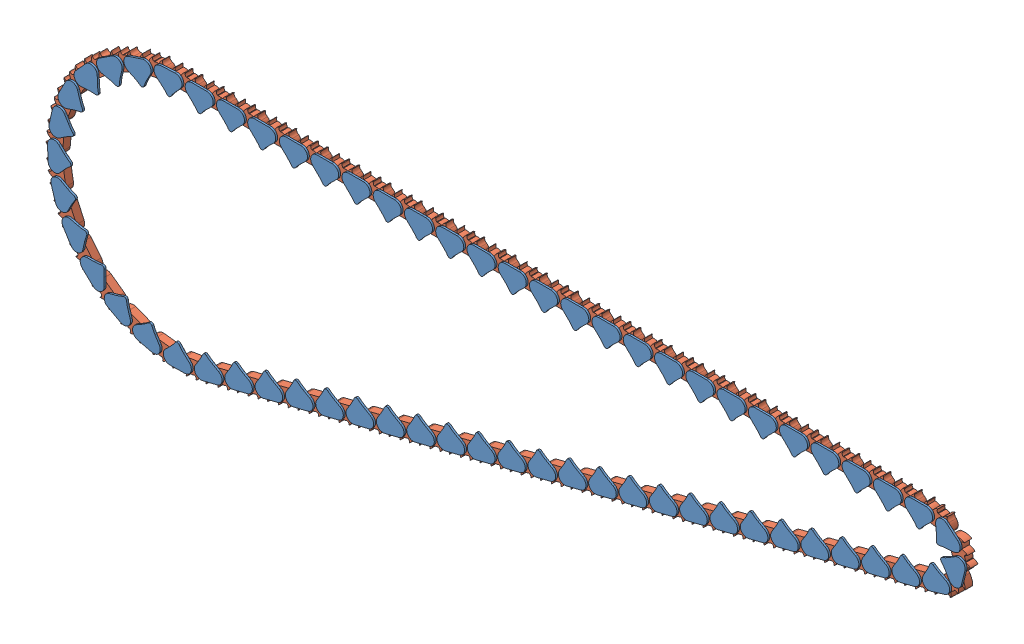
SolidWorks assembly Assem3a, configuration Default. Lengths in mm.
Overall size (244.35 69.57 2.5).
128 component instances, 2 part files, 1 mates.
Components (placement in the parent):
- Inner Part-203: Inner Part [Default] at (-96.4247 54.6348 717.6655) x (-1 0 0) z (0 0 -1) size (7.41 6.1 2.5)
- Teeth-326: Teeth [Default] at (-88.1792 54.6348 717.1655) x (-1 0 0) z (0 0 -1) size (7.83 4.36 2)
- Teeth-327: Teeth [Default] at (-96.4247 54.6348 717.1655) x (-1 0 0) z (0 0 -1) size (7.83 4.36 2)
- Teeth-328: Teeth [Default] at (-104.6702 54.6348 717.1655) x (-1 0 0) z (0 0 -1) size (7.83 4.36 2)
- Teeth-329: Teeth [Default] at (-112.9157 54.6348 717.1655) x (-1 0 0) z (0 0 -1) size (7.83 4.36 2)
- Teeth-330: Teeth [Default] at (-121.1992 54.8708 717.1655) x (-0.981981 -0.188977 0) z (0 0 -1) size (7.83 4.36 2)
- Teeth-331: Teeth [Default] at (-129.3721 53.4391 717.1655) x (-0.901342 -0.433108 0) z (0 0 -1) size (7.83 4.36 2)
- Teeth-332: Teeth [Default] at (-136.91 49.971 717.1655) x (-0.761025 -0.648722 0) z (0 0 -1) size (7.83 4.36 2)
- Teeth-333: Teeth [Default] at (-143.3138 44.6946 717.1655) x (-0.570216 -0.821495 0) z (0 0 -1) size (7.83 4.36 2)
- Teeth-334: Teeth [Default] at (-148.1586 37.9584 717.1655) x (-0.341506 -0.93988 0) z (0 0 -1) size (7.83 4.36 2)
- Teeth-335: Teeth [Default] at (-151.1223 30.2082 717.1655) x (-0.090085 -0.995934 0) z (0 0 -1) size (7.83 4.36 2)
- Teeth-336: Teeth [Default] at (-152.0079 21.9581 717.1655) x (0.167294 -0.985907 0) z (0 0 -1) size (7.83 4.36 2)
- Teeth-337: Teeth [Default] at (-150.7568 13.7555 717.1655) x (0.413488 -0.91051 0) z (0 0 -1) size (7.83 4.36 2)
- Teeth-338: Teeth [Default] at (-147.4526 6.1443 717.1655) x (0.632156 -0.774841 0) z (0 0 -1) size (7.83 4.36 2)
- Teeth-339: Teeth [Default] at (-142.3155 -0.3715 717.1655) x (0.808868 -0.58799 0) z (0 0 -1) size (7.83 4.36 2)
- Teeth-340: Teeth [Default] at (-135.6864 -5.3616 717.1655) x (0.932034 -0.36237 0) z (0 0 -1) size (7.83 4.36 2)
- Teeth-341: Teeth [Default] at (-128.0043 -8.497 717.1655) x (0.993609 -0.112873 0) z (0 0 -1) size (7.83 4.36 2)
- Teeth-342: Teeth [Default] at (-119.7768 -9.5711 717.1655) x (0.989565 0.144089 0) z (0 0 -1) size (7.83 4.36 2)
- Teeth-343: Teeth [Default] at (-111.6404 -8.2623 717.1655) x (0.97022 0.242226 0) z (0 0 -1) size (7.83 4.36 2)
- Teeth-344: Teeth [Default] at (-103.6404 -6.265 717.1655) x (0.97022 0.242226 0) z (0 0 -1) size (7.83 4.36 2)
- Teeth-345: Teeth [Default] at (-95.6405 -4.2677 717.1655) x (0.97022 0.242226 0) z (0 0 -1) size (7.83 4.36 2)
- Teeth-346: Teeth [Default] at (-87.6405 -2.2704 717.1655) x (0.97022 0.242226 0) z (0 0 -1) size (7.83 4.36 2)
- Teeth-347: Teeth [Default] at (-79.6406 -0.2732 717.1655) x (0.97022 0.242226 0) z (0 0 -1) size (7.83 4.36 2)
- Teeth-348: Teeth [Default] at (-71.6406 1.7241 717.1655) x (0.97022 0.242226 0) z (0 0 -1) size (7.83 4.36 2)
- Teeth-349: Teeth [Default] at (-63.6407 3.7214 717.1655) x (0.97022 0.242226 0) z (0 0 -1) size (7.83 4.36 2)
- Teeth-350: Teeth [Default] at (-55.6408 5.7187 717.1655) x (0.97022 0.242226 0) z (0 0 -1) size (7.83 4.36 2)
- Teeth-351: Teeth [Default] at (-47.6408 7.7159 717.1655) x (0.97022 0.242226 0) z (0 0 -1) size (7.83 4.36 2)
- Teeth-352: Teeth [Default] at (-39.6409 9.7132 717.1655) x (0.97022 0.242226 0) z (0 0 -1) size (7.83 4.36 2)
- Teeth-353: Teeth [Default] at (-31.6409 11.7105 717.1655) x (0.97022 0.242226 0) z (0 0 -1) size (7.83 4.36 2)
- Teeth-354: Teeth [Default] at (-23.641 13.7078 717.1655) x (0.97022 0.242226 0) z (0 0 -1) size (7.83 4.36 2)
- Teeth-355: Teeth [Default] at (-15.641 15.705 717.1655) x (0.97022 0.242226 0) z (0 0 -1) size (7.83 4.36 2)
- Teeth-356: Teeth [Default] at (-7.6411 17.7023 717.1655) x (0.97022 0.242226 0) z (0 0 -1) size (7.83 4.36 2)
- Teeth-357: Teeth [Default] at (0.3589 19.6996 717.1655) x (0.97022 0.242226 0) z (0 0 -1) size (7.83 4.36 2)
- Teeth-358: Teeth [Default] at (8.3588 21.6969 717.1655) x (0.97022 0.242226 0) z (0 0 -1) size (7.83 4.36 2)
- Teeth-359: Teeth [Default] at (16.3587 23.6941 717.1655) x (0.97022 0.242226 0) z (0 0 -1) size (7.83 4.36 2)
- Teeth-360: Teeth [Default] at (24.3587 25.6914 717.1655) x (0.97022 0.242226 0) z (0 0 -1) size (7.83 4.36 2)
- Teeth-361: Teeth [Default] at (32.3586 27.6887 717.1655) x (0.97022 0.242226 0) z (0 0 -1) size (7.83 4.36 2)
- Teeth-362: Teeth [Default] at (40.3586 29.686 717.1655) x (0.97022 0.242226 0) z (0 0 -1) size (7.83 4.36 2)
- Teeth-363: Teeth [Default] at (48.3585 31.6832 717.1655) x (0.97022 0.242226 0) z (0 0 -1) size (7.83 4.36 2)
- Teeth-364: Teeth [Default] at (56.3585 33.6805 717.1655) x (0.97022 0.242226 0) z (0 0 -1) size (7.83 4.36 2)
- Teeth-365: Teeth [Default] at (64.3584 35.6778 717.1655) x (0.97022 0.242226 0) z (0 0 -1) size (7.83 4.36 2)
- Teeth-366: Teeth [Default] at (72.3584 37.675 717.1655) x (0.97022 0.242226 0) z (0 0 -1) size (7.83 4.36 2)
- Teeth-367: Teeth [Default] at (80.9343 38.7236 717.1655) x (0.720928 0.69301 0) z (0 0 -1) size (7.83 4.36 2)
- Teeth-368: Teeth [Default] at (87.597 44.8671 717.1655) x (-0.304912 0.95238 0) z (0 0 -1) size (7.83 4.36 2)
- Teeth-369: Teeth [Default] at (85.008 53.5084 717.1655) x (-0.986387 0.164442 0) z (0 0 -1) size (7.83 4.36 2)
- Teeth-370: Teeth [Default] at (76.8558 54.6348 717.1655) x (-1 0 0) z (0 0 -1) size (7.83 4.36 2)
- Teeth-371: Teeth [Default] at (68.6103 54.6348 717.1655) x (-1 0 0) z (0 0 -1) size (7.83 4.36 2)
- Teeth-372: Teeth [Default] at (60.3648 54.6348 717.1655) x (-1 0 0) z (0 0 -1) size (7.83 4.36 2)
- Teeth-373: Teeth [Default] at (52.1193 54.6348 717.1655) x (-1 0 0) z (0 0 -1) size (7.83 4.36 2)
- Teeth-374: Teeth [Default] at (43.8738 54.6348 717.1655) x (-1 0 0) z (0 0 -1) size (7.83 4.36 2)
- Teeth-375: Teeth [Default] at (35.6283 54.6348 717.1655) x (-1 0 0) z (0 0 -1) size (7.83 4.36 2)
- Teeth-376: Teeth [Default] at (27.3828 54.6348 717.1655) x (-1 0 0) z (0 0 -1) size (7.83 4.36 2)
- Teeth-377: Teeth [Default] at (19.1373 54.6348 717.1655) x (-1 0 0) z (0 0 -1) size (7.83 4.36 2)
- Teeth-378: Teeth [Default] at (10.8918 54.6348 717.1655) x (-1 0 0) z (0 0 -1) size (7.83 4.36 2)
- Teeth-379: Teeth [Default] at (2.6463 54.6348 717.1655) x (-1 0 0) z (0 0 -1) size (7.83 4.36 2)
- Teeth-380: Teeth [Default] at (-5.5992 54.6348 717.1655) x (-1 0 0) z (0 0 -1) size (7.83 4.36 2)
- Teeth-381: Teeth [Default] at (-13.8447 54.6348 717.1655) x (-1 0 0) z (0 0 -1) size (7.83 4.36 2)
- Teeth-382: Teeth [Default] at (-22.0902 54.6348 717.1655) x (-1 0 0) z (0 0 -1) size (7.83 4.36 2)
- Teeth-383: Teeth [Default] at (-30.3357 54.6348 717.1655) x (-1 0 0) z (0 0 -1) size (7.83 4.36 2)
- Teeth-384: Teeth [Default] at (-38.5812 54.6348 717.1655) x (-1 0 0) z (0 0 -1) size (7.83 4.36 2)
- Teeth-385: Teeth [Default] at (-46.8267 54.6348 717.1655) x (-1 0 0) z (0 0 -1) size (7.83 4.36 2)
- Teeth-386: Teeth [Default] at (-55.0722 54.6348 717.1655) x (-1 0 0) z (0 0 -1) size (7.83 4.36 2)
- Teeth-387: Teeth [Default] at (-63.3177 54.6348 717.1655) x (-1 0 0) z (0 0 -1) size (7.83 4.36 2)
- Teeth-388: Teeth [Default] at (-71.5632 54.6348 717.1655) x (-1 0 0) z (0 0 -1) size (7.83 4.36 2)
- Teeth-389: Teeth [Default] at (-79.8087 54.6348 717.1655) x (-1 0 0) z (0 0 -1) size (7.83 4.36 2)
- Inner Part-204: Inner Part [Default] at (-104.6702 54.6348 717.6655) x (-1 0 0) z (0 0 -1) size (7.41 6.1 2.5)
- Inner Part-205: Inner Part [Default] at (-112.9157 54.6348 717.6655) x (-1 0 0) z (0 0 -1) size (7.41 6.1 2.5)
- Inner Part-206: Inner Part [Default] at (-121.1586 54.5493 717.6655) x (-0.998125 -0.061215 0) z (0 0 -1) size (7.41 6.1 2.5)
- Inner Part-207: Inner Part [Default] at (-129.2509 53.1385 717.6655) x (-0.949546 -0.313629 0) z (0 0 -1) size (7.41 6.1 2.5)
- Inner Part-208: Inner Part [Default] at (-136.716 49.7111 717.6655) x (-0.838157 -0.545429 0) z (0 0 -1) size (7.41 6.1 2.5)
- Inner Part-209: Inner Part [Default] at (-143.0597 44.4928 717.6655) x (-0.671217 -0.741261 0) z (0 0 -1) size (7.41 6.1 2.5)
- Inner Part-210: Inner Part [Default] at (-147.8612 37.8281 717.6655) x (-0.459699 -0.888075 0) z (0 0 -1) size (7.41 6.1 2.5)
- Inner Part-211: Inner Part [Default] at (-150.8015 30.1582 717.6655) x (-0.217611 -0.976036 0) z (0 0 -1) size (7.41 6.1 2.5)
- Inner Part-212: Inner Part [Default] at (-151.685 21.9916 717.6655) x (0.038936 -0.999242 0) z (0 0 -1) size (7.41 6.1 2.5)
- Inner Part-213: Inner Part [Default] at (-150.4533 13.8703 717.6655) x (0.292843 -0.956161 0) z (0 0 -1) size (7.41 6.1 2.5)
- Inner Part-214: Inner Part [Default] at (-147.1886 6.3327 717.6655) x (0.527221 -0.849728 0) z (0 0 -1) size (7.41 6.1 2.5)
- Inner Part-215: Inner Part [Default] at (-142.1084 -0.1222 717.6655) x (0.726557 -0.687106 0) z (0 0 -1) size (7.41 6.1 2.5)
- Inner Part-216: Inner Part [Default] at (-135.5498 -5.0679 717.6655) x (0.877737 -0.479142 0) z (0 0 -1) size (7.41 6.1 2.5)
- Inner Part-217: Inner Part [Default] at (-127.9471 -8.1782 717.6655) x (0.970871 -0.239604 0) z (0 0 -1) size (7.41 6.1 2.5)
- Inner Part-218: Inner Part [Default] at (-119.8028 -9.2482 717.6655) x (0.999876 0.015731 0) z (0 0 -1) size (7.41 6.1 2.5)
- Inner Part-219: Inner Part [Default] at (-111.6429 -8.2518 717.6655) x (0.971247 0.238075 0) z (0 0 -1) size (7.41 6.1 2.5)
- Inner Part-220: Inner Part [Default] at (-103.6404 -6.265 717.6655) x (0.97022 0.242226 0) z (0 0 -1) size (7.41 6.1 2.5)
- Inner Part-221: Inner Part [Default] at (-95.6405 -4.2677 717.6655) x (0.97022 0.242226 0) z (0 0 -1) size (7.41 6.1 2.5)
- Inner Part-222: Inner Part [Default] at (-87.6405 -2.2704 717.6655) x (0.97022 0.242226 0) z (0 0 -1) size (7.41 6.1 2.5)
- Inner Part-223: Inner Part [Default] at (-79.6406 -0.2732 717.6655) x (0.97022 0.242226 0) z (0 0 -1) size (7.41 6.1 2.5)
- Inner Part-224: Inner Part [Default] at (-71.6406 1.7241 717.6655) x (0.97022 0.242226 0) z (0 0 -1) size (7.41 6.1 2.5)
- Inner Part-225: Inner Part [Default] at (-63.6407 3.7214 717.6655) x (0.97022 0.242226 0) z (0 0 -1) size (7.41 6.1 2.5)
- Inner Part-226: Inner Part [Default] at (-55.6408 5.7187 717.6655) x (0.97022 0.242226 0) z (0 0 -1) size (7.41 6.1 2.5)
- Inner Part-227: Inner Part [Default] at (-47.6408 7.7159 717.6655) x (0.97022 0.242226 0) z (0 0 -1) size (7.41 6.1 2.5)
- Inner Part-228: Inner Part [Default] at (-39.6409 9.7132 717.6655) x (0.97022 0.242226 0) z (0 0 -1) size (7.41 6.1 2.5)
- Inner Part-229: Inner Part [Default] at (-31.6409 11.7105 717.6655) x (0.97022 0.242226 0) z (0 0 -1) size (7.41 6.1 2.5)
- Inner Part-230: Inner Part [Default] at (-23.641 13.7078 717.6655) x (0.97022 0.242226 0) z (0 0 -1) size (7.41 6.1 2.5)
- Inner Part-231: Inner Part [Default] at (-15.641 15.705 717.6655) x (0.97022 0.242226 0) z (0 0 -1) size (7.41 6.1 2.5)
- Inner Part-232: Inner Part [Default] at (-7.6411 17.7023 717.6655) x (0.97022 0.242226 0) z (0 0 -1) size (7.41 6.1 2.5)
- Inner Part-233: Inner Part [Default] at (0.3589 19.6996 717.6655) x (0.97022 0.242226 0) z (0 0 -1) size (7.41 6.1 2.5)
- Inner Part-234: Inner Part [Default] at (8.3588 21.6969 717.6655) x (0.97022 0.242226 0) z (0 0 -1) size (7.41 6.1 2.5)
- Inner Part-235: Inner Part [Default] at (16.3587 23.6941 717.6655) x (0.97022 0.242226 0) z (0 0 -1) size (7.41 6.1 2.5)
- Inner Part-236: Inner Part [Default] at (24.3587 25.6914 717.6655) x (0.97022 0.242226 0) z (0 0 -1) size (7.41 6.1 2.5)
- Inner Part-237: Inner Part [Default] at (32.3586 27.6887 717.6655) x (0.97022 0.242226 0) z (0 0 -1) size (7.41 6.1 2.5)
- Inner Part-238: Inner Part [Default] at (40.3586 29.686 717.6655) x (0.97022 0.242226 0) z (0 0 -1) size (7.41 6.1 2.5)
- Inner Part-239: Inner Part [Default] at (48.3585 31.6832 717.6655) x (0.97022 0.242226 0) z (0 0 -1) size (7.41 6.1 2.5)
- Inner Part-240: Inner Part [Default] at (56.3585 33.6805 717.6655) x (0.97022 0.242226 0) z (0 0 -1) size (7.41 6.1 2.5)
- Inner Part-241: Inner Part [Default] at (64.3584 35.6778 717.6655) x (0.97022 0.242226 0) z (0 0 -1) size (7.41 6.1 2.5)
- Inner Part-242: Inner Part [Default] at (72.3584 37.675 717.6655) x (0.97022 0.242226 0) z (0 0 -1) size (7.41 6.1 2.5)
- Inner Part-243: Inner Part [Default] at (80.34 39.7385 717.6655) x (0.957144 0.289613 0) z (0 0 -1) size (7.41 6.1 2.5)
- Inner Part-244: Inner Part [Default] at (86.2141 44.8239 717.6655) x (0.244795 0.969575 0) z (0 0 -1) size (7.41 6.1 2.5)
- Inner Part-245: Inner Part [Default] at (84.4443 52.2939 717.6655) x (-0.762337 0.64718 0) z (0 0 -1) size (7.41 6.1 2.5)
- Inner Part-246: Inner Part [Default] at (76.8558 54.6348 717.6655) x (-1 0 0) z (0 0 -1) size (7.41 6.1 2.5)
- Inner Part-247: Inner Part [Default] at (68.6103 54.6348 717.6655) x (-1 0 0) z (0 0 -1) size (7.41 6.1 2.5)
- Inner Part-248: Inner Part [Default] at (60.3648 54.6348 717.6655) x (-1 0 0) z (0 0 -1) size (7.41 6.1 2.5)
- Inner Part-249: Inner Part [Default] at (52.1193 54.6348 717.6655) x (-1 0 0) z (0 0 -1) size (7.41 6.1 2.5)
- Inner Part-250: Inner Part [Default] at (43.8738 54.6348 717.6655) x (-1 0 0) z (0 0 -1) size (7.41 6.1 2.5)
- Inner Part-251: Inner Part [Default] at (35.6283 54.6348 717.6655) x (-1 0 0) z (0 0 -1) size (7.41 6.1 2.5)
- Inner Part-252: Inner Part [Default] at (27.3828 54.6348 717.6655) x (-1 0 0) z (0 0 -1) size (7.41 6.1 2.5)
- Inner Part-253: Inner Part [Default] at (19.1373 54.6348 717.6655) x (-1 0 0) z (0 0 -1) size (7.41 6.1 2.5)
- Inner Part-254: Inner Part [Default] at (10.8918 54.6348 717.6655) x (-1 0 0) z (0 0 -1) size (7.41 6.1 2.5)
- Inner Part-255: Inner Part [Default] at (2.6463 54.6348 717.6655) x (-1 0 0) z (0 0 -1) size (7.41 6.1 2.5)
- Inner Part-256: Inner Part [Default] at (-5.5992 54.6348 717.6655) x (-1 0 0) z (0 0 -1) size (7.41 6.1 2.5)
- Inner Part-257: Inner Part [Default] at (-13.8447 54.6348 717.6655) x (-1 0 0) z (0 0 -1) size (7.41 6.1 2.5)
- Inner Part-258: Inner Part [Default] at (-22.0902 54.6348 717.6655) x (-1 0 0) z (0 0 -1) size (7.41 6.1 2.5)
- Inner Part-259: Inner Part [Default] at (-30.3357 54.6348 717.6655) x (-1 0 0) z (0 0 -1) size (7.41 6.1 2.5)
- Inner Part-260: Inner Part [Default] at (-38.5812 54.6348 717.6655) x (-1 0 0) z (0 0 -1) size (7.41 6.1 2.5)
- Inner Part-261: Inner Part [Default] at (-46.8267 54.6348 717.6655) x (-1 0 0) z (0 0 -1) size (7.41 6.1 2.5)
- Inner Part-262: Inner Part [Default] at (-55.0722 54.6348 717.6655) x (-1 0 0) z (0 0 -1) size (7.41 6.1 2.5)
- Inner Part-263: Inner Part [Default] at (-63.3177 54.6348 717.6655) x (-1 0 0) z (0 0 -1) size (7.41 6.1 2.5)
- Inner Part-264: Inner Part [Default] at (-71.5632 54.6348 717.6655) x (-1 0 0) z (0 0 -1) size (7.41 6.1 2.5)
- Inner Part-265: Inner Part [Default] at (-79.8087 54.6348 717.6655) x (-1 0 0) z (0 0 -1) size (7.41 6.1 2.5)
- Inner Part-266: Inner Part [Default] at (-88.0542 54.6348 717.6655) x (-1 0 0) z (0 0 -1) size (7.41 6.1 2.5)
Mates (geometry in assembly coordinates):
- Concentric5: concentric: cylinder of Inner Part-203 through (-95.0288 54.6348 717.6655) axis (0 0 -1) radius 0.6; cylinder of Teeth-326 through (-95.0288 54.6348 717.1655) axis (0 0 -1) radius 0.6
